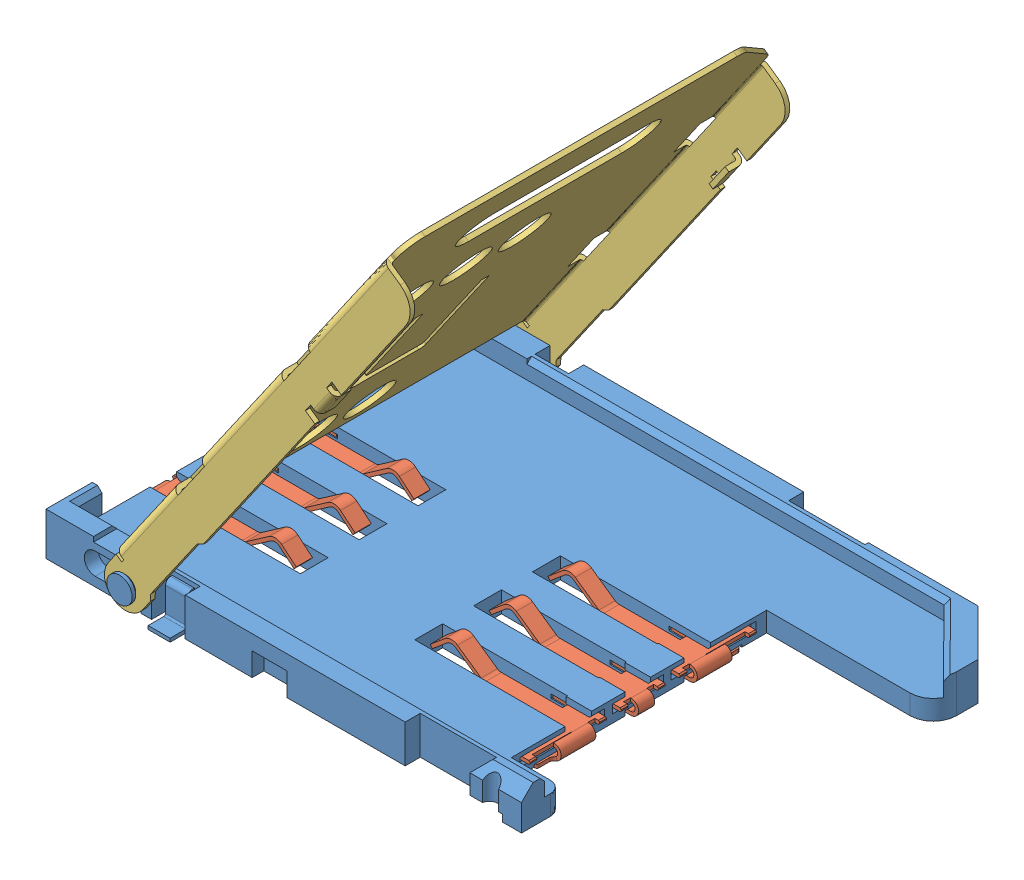
SolidWorks assembly 473880001, SIM, Assembly, configuration Default. Lengths in mm.
Overall size (25.52 19.81 18.1).
3 component instances, 3 part files, 9 mates.
Components (placement in the parent):
- 473880001, SIM, Base-1: 473880001, SIM, Base [Default] at origin size (25.52 1.9 18.1)
- 473880001, SIM, Contacts-1: 473880001, SIM, Contacts [Default] at (0.0008 0.45 0) x (-1 0 0) z (0 0 -1) size (18.69 1.51 9.78)
- 473880001, SIM, Lid-1: 473880001, SIM, Lid [Default] at (-7.1108 -2.5474 7.16) x (0.571717 0.820451 0) z (0 0 1) size (22.8 1.93 17.7)
Mates (geometry in assembly coordinates):
- Coincident1: coincident aligned: plane of 473880001, SIM, Base-1 through (0 0 0) normal (1 0 0); plane of assembly through (0 0 0) normal (1 0 0)
- Coincident2: coincident aligned: plane of 473880001, SIM, Base-1 through (0 0 0) normal (0 1 0); plane of assembly through (0 0 0) normal (0 1 0)
- Coincident3: coincident aligned: plane of 473880001, SIM, Base-1 through (0 0 0) normal (0 0 1); plane of assembly through (0 0 0) normal (0 0 1)
- Coincident4: coincident anti-aligned: plane of 473880001, SIM, Base-1 through (-7.855 0.45 -3.14) normal (0 1 0); plane of 473880001, SIM, Contacts-1 through (9.01 0.45 -2.19) normal (0 -1 0)
- Distance1: distance = 0.075 mm aligned: plane of 473880001, SIM, Contacts-1 through (-9.03 0.6 -2.19) normal (-1 0 0); plane of 473880001, SIM, Base-1 through (-8.955 1.9 5.21) normal (-1 0 0)
- Distance2: distance = 0.05 mm anti-aligned: plane of 473880001, SIM, Contacts-1 through (-9.23 0.6 -1.59) normal (0 0 1); plane of 473880001, SIM, Base-1 through (-8.955 0.45 -1.54) normal (0 0 -1)
- Concentric1: concentric aligned: cylinder of 473880001, SIM, Base-1 through (-5.755 0.92 6.41) axis (0 0 1) radius 0.375; cylinder of 473880001, SIM, Lid-1 through (-5.755 0.92 7.21) axis (0 0 1) radius 0.45
- Coincident10: coincident anti-aligned: plane of 473880001, SIM, Base-1 through (-9.375 0.05 7.21) normal (0 0 1); plane of 473880001, SIM, Lid-1 through (-7.1108 -2.5474 7.21) normal (0 0 -1)
- LimitAngle2: limit planar angle = 2.179394 rad aligned: plane of 473880001, SIM, Lid-1 through (6.0846 19.3624 7.11) normal (0.820451 -0.571717 0); plane of 473880001, SIM, Base-1 through (-7.325 1.69 7.21) normal (0 1 0)
